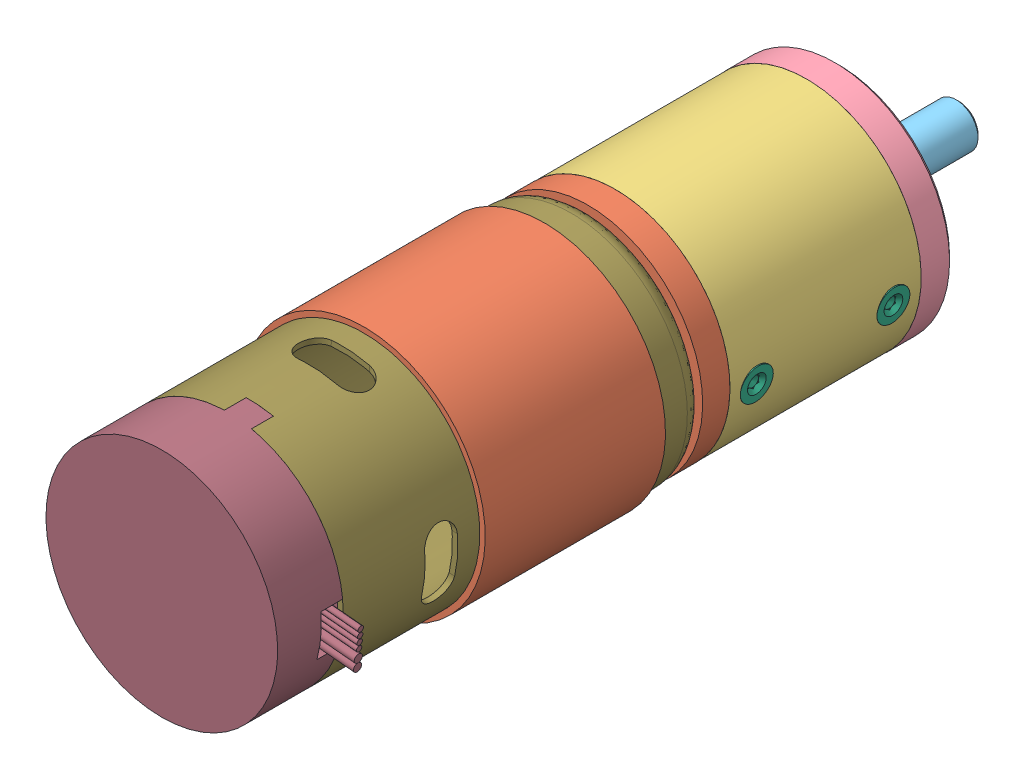
SolidWorks assembly IG42-24(1,49), configuration Default. Lengths in mm.
Overall size (136.69 72.45 716.58).
27 component instances, 20 part files, 27 mates.
Components (placement in the parent):
- retaining-ring_3cm1-8-1: retaining-ring_3cm1-8 [Default] at (9.8685 8.1812 7.7542) size (14.6 12.42 0.6)
- 1-1: 1 [Default] at (9.8685 8.1812 55.9542) x (-0.9958 0.091554 0) z (-0.091554 -0.9958 0) size (42 40 42)
- 2-1: 2 [Default] at (9.8685 8.1812 50.9542) x (-0.091554 -0.9958 0) z (0.9958 -0.091554 0) size (42 35 42)
- 3-1: 3 [Default] at (9.8685 8.1812 10.0542) x (0 0 1) z (0.9958 -0.091554 0) size (7.9 42 42)
- 4-1: 4 [Default] at (9.8685 8.1812 8.0542) x (0.936864 -0.349695 0) z (0.349695 0.936864 0) size (8 30 8)
- (24300)M3x6-1: (24300)M3x6 [Default] at (-9.3504 9.9482 20.9542) x (0.9958 -0.091554 0) z (0.085471 0.92963 0.358444) size (6 6 6)
- (24300)M3x6-2: (24300)M3x6 [Default] at (-9.3504 9.9482 45.9542) x (0.9958 -0.091554 0) z (0 0 1) size (6 6 6)
- (24300)M3x6-3: (24300)M3x6 [Default] at (8.1016 -11.0377 20.9542) x (0.091554 0.9958 0) z (0 0 1) size (6 6 6)
- (24300)M3x6-4: (24300)M3x6 [Default] at (29.0875 6.4142 20.9542) x (-0.9958 0.091554 0) z (0 0 1) size (6 6 6)
- (24300)M3x6-5: (24300)M3x6 [Default] at (29.0875 6.4142 45.9542) x (-0.9958 0.091554 0) z (0 0 1) size (6 6 6)
- roulement_628_8-2z_2-1: roulement_628_8-2z_2 [Default] at (9.8685 8.1812 8.0542) x (0 0 1) z (-0.022443 0.999748 0) size (5 16 16)
  - roulement_628_8-2z_2_01-1: roulement_628_8-2z_2_01 [Default] at origin size (5 16 16)
  - roulement_628_8-2z_2_02-1: roulement_628_8-2z_2_02 [Default] at origin size (5 10.1 10.1)
  - roulement_628_8-2z_2_03-1: roulement_628_8-2z_2_03 [Default] at origin size (0.27 14.44 14.44)
  - roulement_628_8-2z_2_04-1: roulement_628_8-2z_2_04 [Default] at origin size (0.27 14.44 14.44)
  - roulement_628_8-2z_2_05-1: roulement_628_8-2z_2_05 [Default] at origin size (2.38 13.92 14.1)
- IG42,PG420,MG49 DC Motor-1: IG42,PG420,MG49 DC Motor [Default] at (-399.0954 363.1346 -91.1079) x (0 0 1) z (0.9958 -0.091554 0) size (663.68 60.65 131.7)
  - Part1-1: Part1 [Default] at (142.3621 316.0202 439.7438) size (653.38 42.4 122.57)
  - Part2-1: Part2 [Default] at (225.0621 316.0202 439.7438) x (0 1 0) z (0 0 1) size (42.4 20 47.4)
  - Part3-1: Part3 [Default] at (147.0621 316.0202 439.7438) x (0 1 0) z (0 0 1) size (5 15 5)
  - roulement_625-2z_2-1: roulement_625-2z_2 [Default] at (142.0621 316.0202 439.7438) size (5 16 16)
    - roulement_625-2z_2_01-1: roulement_625-2z_2_01 [Default] at origin size (5 16 16)
    - roulement_625-2z_2_02-1: roulement_625-2z_2_02 [Default] at origin size (5 8.4 8.4)
    - roulement_625-2z_2_03-1: roulement_625-2z_2_03 [Default] at origin size (0.55 13.71 13.71)
    - roulement_625-2z_2_04-1: roulement_625-2z_2_04 [Default] at origin size (0.55 13.71 13.71)
    - roulement_625-2z_2_05-1: roulement_625-2z_2_05 [Default] at origin size (2.38 12.58 12.58)
  - Part4-1: Part4 [Default] at (155.0621 316.0202 439.7438) x (1 0 0) z (0 -0.5 0.866025) size (33 44.4 44.4)
Mates (geometry in assembly coordinates):
- Coincident1: coincident anti-aligned: plane of 1-1 through (9.8685 8.1812 50.9542) normal (0 0 -1); plane of 2-1 through (9.8685 8.1812 50.9542) normal (0 0 1)
- Concentric1: concentric aligned: cylinder of 1-1 through (9.8685 8.1812 50.9542) axis (0 0 1) radius 21; cylinder of 2-1 through (9.8685 8.1812 15.9542) axis (0 0 1) radius 21
- Coincident2: coincident anti-aligned: plane of 2-1 through (9.8685 8.1812 15.9542) normal (0 0 -1); plane of 3-1 through (7.9459 -12.7306 15.9542) normal (0 0 1)
- Concentric2: concentric anti-aligned: cylinder of 2-1 through (9.8685 8.1812 15.9542) axis (0 0 1) radius 21; cylinder of 3-1 through (9.8685 8.1812 10.0542) axis (0 0 -1) radius 21
- Concentric3: concentric anti-aligned: cylinder of retaining-ring_3cm1-8-1 through (9.8685 8.1812 9.0542) axis (0 0 -1) radius 3.2; cylinder of 4-1 through (9.8685 8.1812 8.0542) axis (0 0 1) radius 3.2
- Concentric4: concentric aligned: cylinder of 3-1 through (9.8685 8.1812 8.0542) axis (0 0 1) radius 8; cylinder of 4-1 through (9.8685 8.1812 18.0542) axis (0 0 1) radius 4
- Coincident3: coincident anti-aligned: plane of retaining-ring_3cm1-8-1 through (5.6865 3.6965 8.0542) normal (0 0 1); plane of 3-1 through (9.8685 8.1812 8.0542) normal (0 0 -1)
- Coincident4: coincident anti-aligned: plane of retaining-ring_3cm1-8-1 through (5.6865 3.6965 7.4542) normal (0 0 -1); plane of 4-1 through (8.1544 3.5888 7.4542) normal (0 0 1)
- Concentric6: concentric aligned: cylinder of 2-1 through (30.7818 6.2584 20.9542) axis (-0.9958 0.091554 0) radius 1.5; cylinder of (24300)M3x6-1 through (-7.362 9.7654 20.9542) axis (-0.9958 0.091554 0) radius 1.5
- Tangent2: tangent aligned: cylinder of 2-1 through (9.8685 8.1812 15.9542) axis (0 0 1) radius 21; plane of (24300)M3x6-1 through (-11.2444 7.9159 20.1106) normal (-0.9958 0.091554 0)
- Concentric8: concentric aligned: cylinder of 2-1 through (30.7818 6.2584 45.9542) axis (-0.9958 0.091554 0) radius 1.5; cylinder of (24300)M3x6-2 through (-7.362 9.7654 45.9542) axis (-0.9958 0.091554 0) radius 1.5
- Tangent3: tangent aligned: cylinder of 2-1 through (9.8685 8.1812 15.9542) axis (0 0 1) radius 21; plane of (24300)M3x6-2 through (-11.0433 10.1038 43.6006) normal (-0.9958 0.091554 0)
- Concentric9: concentric aligned: cylinder of 2-1 through (11.7913 29.094 20.9542) axis (-0.091554 -0.9958 0) radius 1.5; cylinder of (24300)M3x6-3 through (8.2844 -9.0494 20.9542) axis (-0.091554 -0.9958 0) radius 1.5
- Tangent4: tangent aligned: cylinder of 2-1 through (9.8685 8.1812 15.9542) axis (0 0 1) radius 21; plane of (24300)M3x6-3 through (7.9459 -12.7306 18.6006) normal (-0.091554 -0.9958 0)
- Concentric10: concentric aligned: cylinder of 2-1 through (-11.0442 10.1039 20.9542) axis (0.9958 -0.091554 0) radius 1.5; cylinder of (24300)M3x6-4 through (27.0991 6.597 20.9542) axis (0.9958 -0.091554 0) radius 1.5
- Tangent5: tangent aligned: cylinder of 2-1 through (9.8685 8.1812 15.9542) axis (0 0 1) radius 21; plane of (24300)M3x6-4 through (30.7804 6.2586 18.6006) normal (0.9958 -0.091554 0)
- Concentric13: concentric aligned: cylinder of 2-1 through (-11.0442 10.1039 45.9542) axis (0.9958 -0.091554 0) radius 1.5; cylinder of (24300)M3x6-5 through (27.0991 6.597 45.9542) axis (0.9958 -0.091554 0) radius 1.5
- Tangent6: tangent aligned: cylinder of 2-1 through (9.8685 8.1812 15.9542) axis (0 0 1) radius 21; plane of (24300)M3x6-5 through (30.7804 6.2586 43.6006) normal (0.9958 -0.091554 0)
- Coincident5: coincident: point of 2-1; point of 1-1
- Parallel1: parallel aligned: plane of 3-1 through (21.7688 12.0067 8.0542) normal (0.9958 -0.091554 0); plane of (24300)M3x6-4 through (30.7804 6.2586 18.6006) normal (0.9958 -0.091554 0)
- Concentric14: concentric anti-aligned: cylinder of 3-1 through (9.8685 8.1812 8.0542) axis (0 0 1) radius 8; cylinder of roulement_628_8-2z_2-1/roulement_628_8-2z_2_01-1 through (9.8685 8.1812 8.0542) axis (0 0 -1) radius 8
- Coincident6: coincident anti-aligned: plane of 3-1 through (9.8685 8.1812 13.0542) normal (0 0 -1); plane of roulement_628_8-2z_2-1/roulement_628_8-2z_2_02-1 through (14.0675 8.2755 13.0542) normal (0 0 1)
- Lock1: lock: unknown of 4-1; unknown of roulement_628_8-2z_2-1/roulement_628_8-2z_2_02-1
- Concentric15: concentric anti-aligned: cylinder of 2-1 through (9.8685 8.1812 15.9542) axis (0 0 1) radius 21; cylinder of IG42,PG420,MG49 DC Motor-1/Part1-1 through (9.8685 8.1812 51.2542) axis (0 0 -1) radius 21.2
- Concentric16: concentric anti-aligned: cylinder of 1-1 through (19.1398 -2.9675 50.9542) axis (0 0 1) radius 2.1; cylinder of IG42,PG420,MG49 DC Motor-1/Part1-1 through (19.1398 -2.9675 121.9552) axis (0 0 -1) radius 2
- Concentric17: concentric anti-aligned: cylinder of 1-1 through (0.5973 19.3299 50.9542) axis (0 0 1) radius 2.1; cylinder of IG42,PG420,MG49 DC Motor-1/Part1-1 through (0.5973 19.3299 121.9552) axis (0 0 -1) radius 2
- Coincident8: coincident anti-aligned: plane of 1-1 through (9.8685 8.1812 55.9542) normal (0 0 1); plane of IG42,PG420,MG49 DC Motor-1/Part1-1 through (8.2023 -9.9424 55.9542) normal (0 0 -1)
